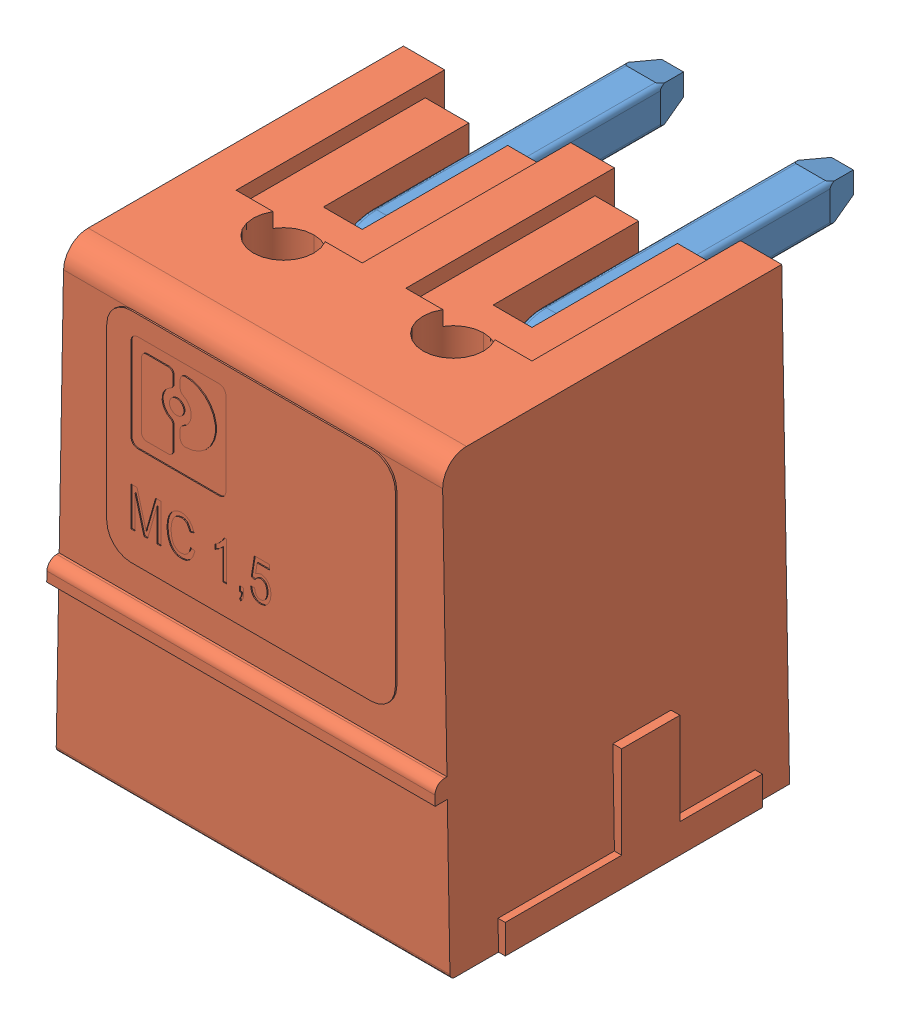
SolidWorks assembly phoenix_2pos_horiz_pxc_1844210_05_MC-1-5-2-G-3-5_3D, configuration Default. Lengths in mm.
Overall size (8.4 9.2 10.65).
4 component instances, 2 part files, 0 mates.
Components (placement in the parent):
- pxc_1844210_05_MC-1-5-2-G-3-5_3D.stp-1: pxc_1844210_05_MC-1-5-2-G-3-5_3D.stp [Default] at origin size (8.4 9.2 10.65)
  - LP_MC_1_5_G_3_5.6.stp-1: LP_MC_1_5_G_3_5.6.stp [Default] at (-38.5887 53.1745 3.4) x (0 -1 0) z (0 0 1) size (7.2 0.8 6.8)
  - AT_MC_1_5_G_3_5.stp-1: AT_MC_1_5_G_3_5.stp [Default] at (-10.5144 -62.2013 2.8174) x (0 -1 0) z (-1 0 0) size (9.2 7.25 8.4)
  - LP_MC_1_5_G_3_5.6.stp-2: LP_MC_1_5_G_3_5.6.stp [Default] at (-35.0887 53.1745 3.4) x (0 -1 0) z (0 0 1) size (7.2 0.8 6.8)
